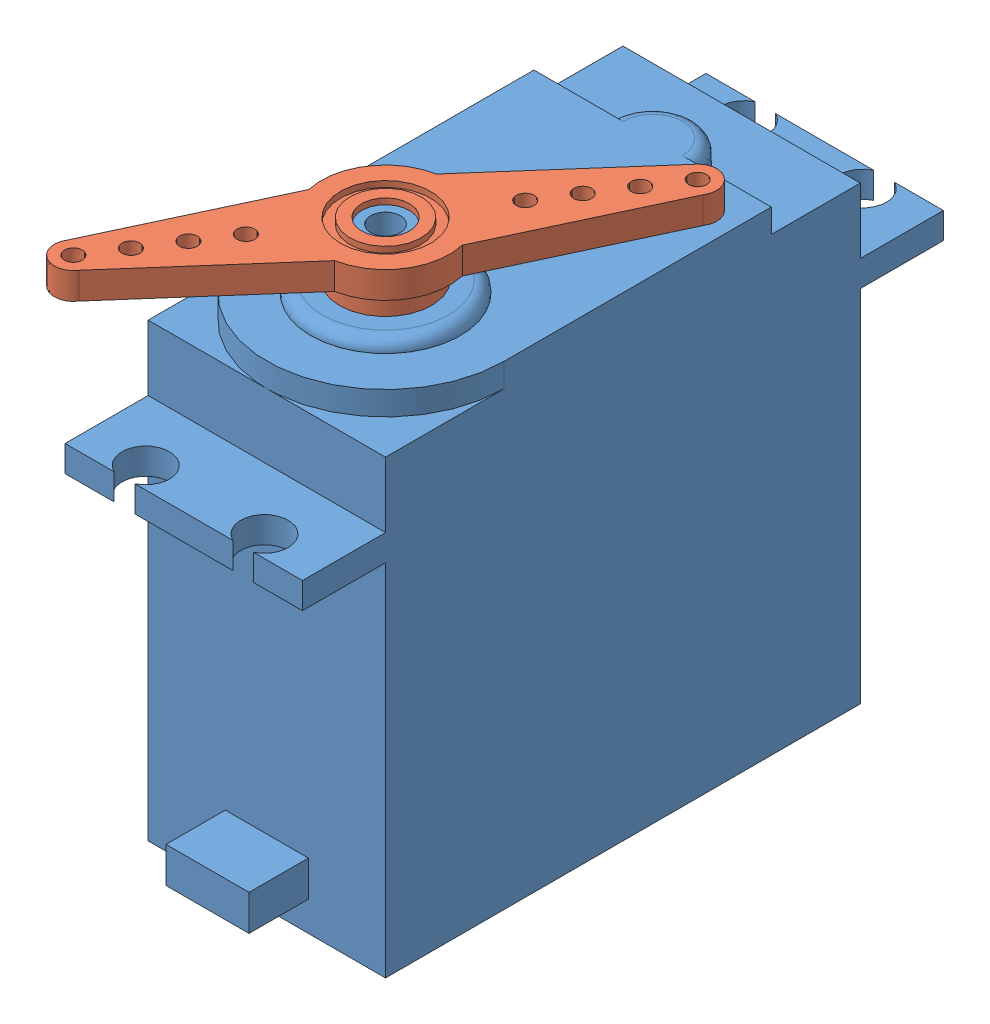
SolidWorks assembly servo Assem, configuration Default. Lengths in mm.
Overall size (31.58 45.5 57.2).
2 component instances, 2 part files, 2 mates.
Components (placement in the parent):
- servo strong junk 2-2: servo strong junk 2 [Default] at (33.4839 -39.4715 49.0094) size (20 45 54)
- servo strong junk 1-2: servo strong junk 1 [Default] at (43.4839 6.0285 39.0094) x (-0.837169 0 -0.546944) z (-0.546944 0 0.837169) size (10.8 4.5 41.2)
Mates (geometry in assembly coordinates):
- Concentric2: concentric: cylinder of servo strong junk 2-2 through (43.4839 5.5285 39.0094) axis (0 -1 0) radius 2.5; cylinder of servo strong junk 1-2 through (43.4839 3.7785 39.0094) axis (0 1 0) radius 2.5
- Coincident2: coincident anti-aligned: plane of servo strong junk 2-2 through (43.4839 1.5285 39.0094) normal (0 1 0); plane of servo strong junk 1-2 through (43.4839 1.5285 39.0094) normal (0 -1 0)
